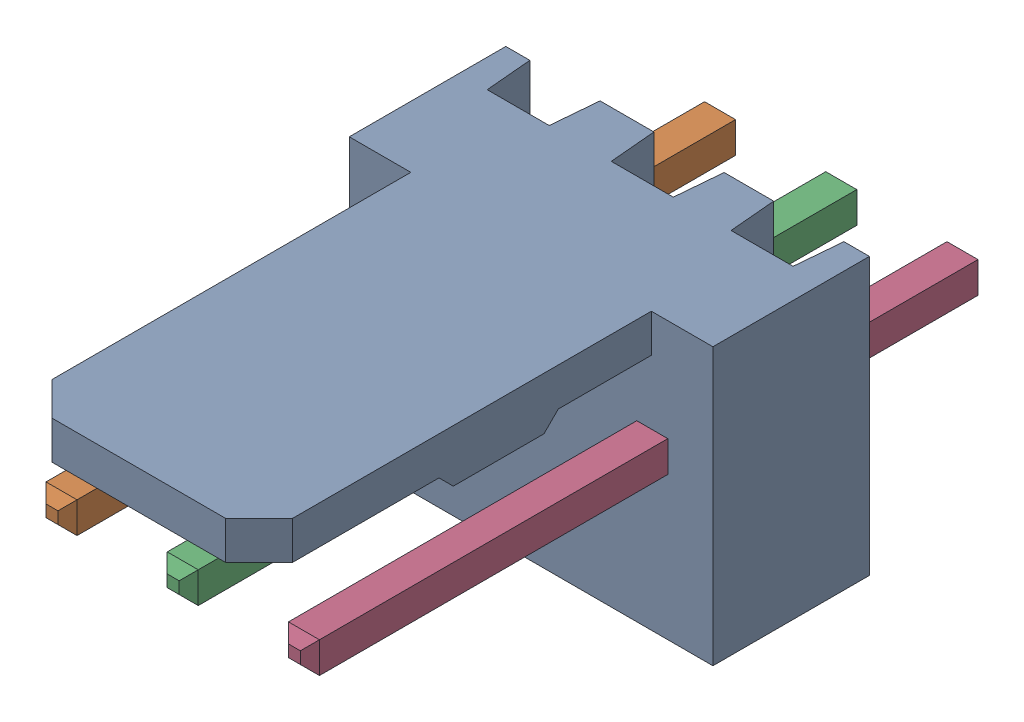
SolidWorks assembly Molex PCB 3 pin v2 v6_2, configuration Default. Lengths in mm.
Overall size (7.62 5.79 14.92).
4 component instances, 2 part files, 0 mates.
Components (placement in the parent):
- BASE9710016_2-1: BASE9710016_2 [Default] at (2.54 2.895 -8.22) size (7.62 5.79 11.5)
- PINO9710016_2-1: PINO9710016_2 [Default] at (1.27 3.325 -0.72) size (0.65 0.65 14.2)
- PINO9710016_2-2: PINO9710016_2 [Default] at (3.81 3.325 -0.72) size (0.65 0.65 14.2)
- PINO9710016_2-3: PINO9710016_2 [Default] at (6.35 3.325 -0.72) size (0.65 0.65 14.2)
